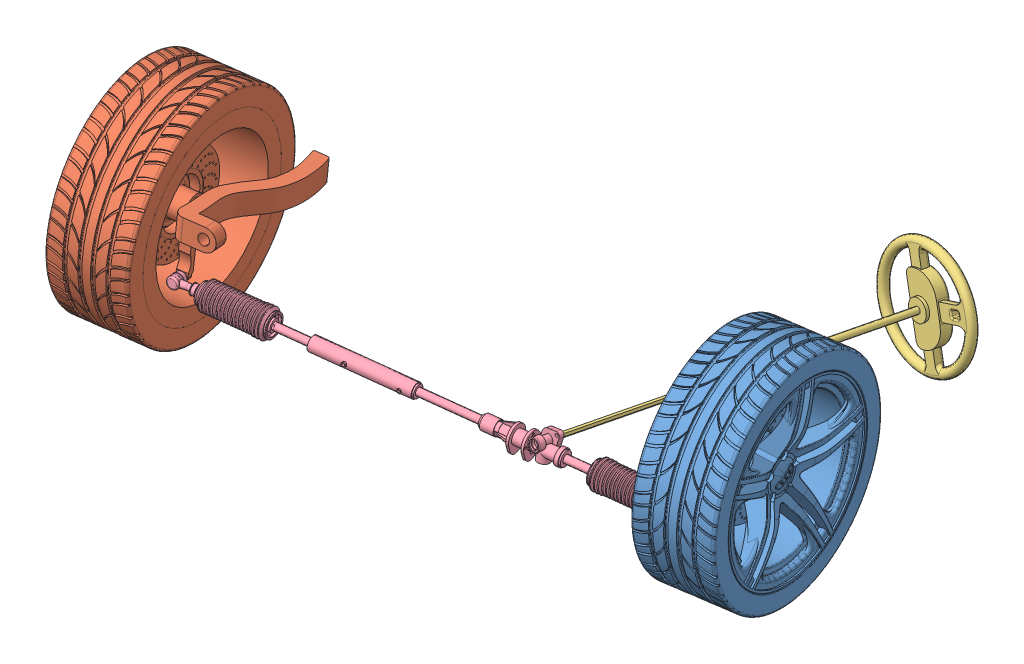
SolidWorks assembly thanh_rack, configuration Default. Lengths in mm.
Overall size (2100.56 980.29 1754.93).
4 component instances, 4 part files, 6 mates.
Components (placement in the parent):
- Left_wheel-1: Left_wheel [Default] at (-453.0498 134.4657 -22.7515) x (-0.138647 0.469574 -0.871939) z (-0.092494 -0.882734 -0.46068) size (668.92 361.62 668.92)
- right_wheel-1: right_wheel [Default] at (-1161.904 182.778 91.4539) x (-0.985893 0.031278 0.164427) z (0.014411 0.994599 -0.102792) size (361.62 859.68 828.84)
- Steering_wheel_steering_column-1: Steering_wheel_steering_column [Default] at (-18.3723 -94.341 -1099.5525) x (-0.332807 0.932599 -0.139638) z (0.103454 -0.111077 -0.988412) size (350 350 1180.07)
- Tie_rod_components_new-1: Tie_rod_components_new [Default] at (1.9911 6.876 10.2468) x (0.051355 0.997337 0.05179) z (-0.985692 0.042282 0.163165) size (98.29 100.41 1505.65)
Mates (geometry in assembly coordinates):
- Concentric6: concentric anti-aligned: cylinder of Left_wheel-1 through (281.8472 -5.8135 -42.5191) axis (-0.166668 -0.100074 -0.980921) radius 6; cylinder of Tie_rod_components_new-1 through (280.0278 -6.906 -53.227) axis (0.166668 0.100074 0.980921) radius 6.4528
- Coincident7: coincident anti-aligned: plane of Left_wheel-1 through (295.5357 -16.7836 -61.0263) normal (0.166668 0.100074 0.980921); plane of Tie_rod_components_new-1 through (279.181 -1.0972 -59.8479) normal (-0.166668 -0.100074 -0.980921)
- Concentric9: concentric anti-aligned: cylinder of right_wheel-1 through (-1165.3 56.2043 197.038) axis (-0.166895 -0.109339 -0.979893) radius 6; cylinder of Tie_rod_components_new-1 through (-1167.1219 55.0108 186.3413) axis (0.166895 0.109339 0.979893) radius 6.4528
- Coincident13: coincident anti-aligned: plane of right_wheel-1 through (-1184.6356 55.6937 183.0694) normal (0.166895 0.109339 0.979893); plane of Tie_rod_components_new-1 through (-1168.2846 47.9404 181.1497) normal (-0.166895 -0.109339 -0.979893)
- Concentric11: concentric aligned: cylinder of Steering_wheel_steering_column-1 through (-18.8896 -93.7856 -1094.6104) axis (-0.103454 0.111077 0.988412) radius 10; cylinder of Tie_rod_components_new-1 through (-128.1759 23.5537 -50.4728) axis (-0.103454 0.111077 0.988412) radius 12.76
- Coincident15: coincident anti-aligned: plane of Steering_wheel_steering_column-1 through (-138.327 34.4528 46.5118) normal (-0.103454 0.111077 0.988412); plane of Tie_rod_components_new-1 through (-138.327 34.4528 46.5118) normal (0.103454 -0.111077 -0.988412)
